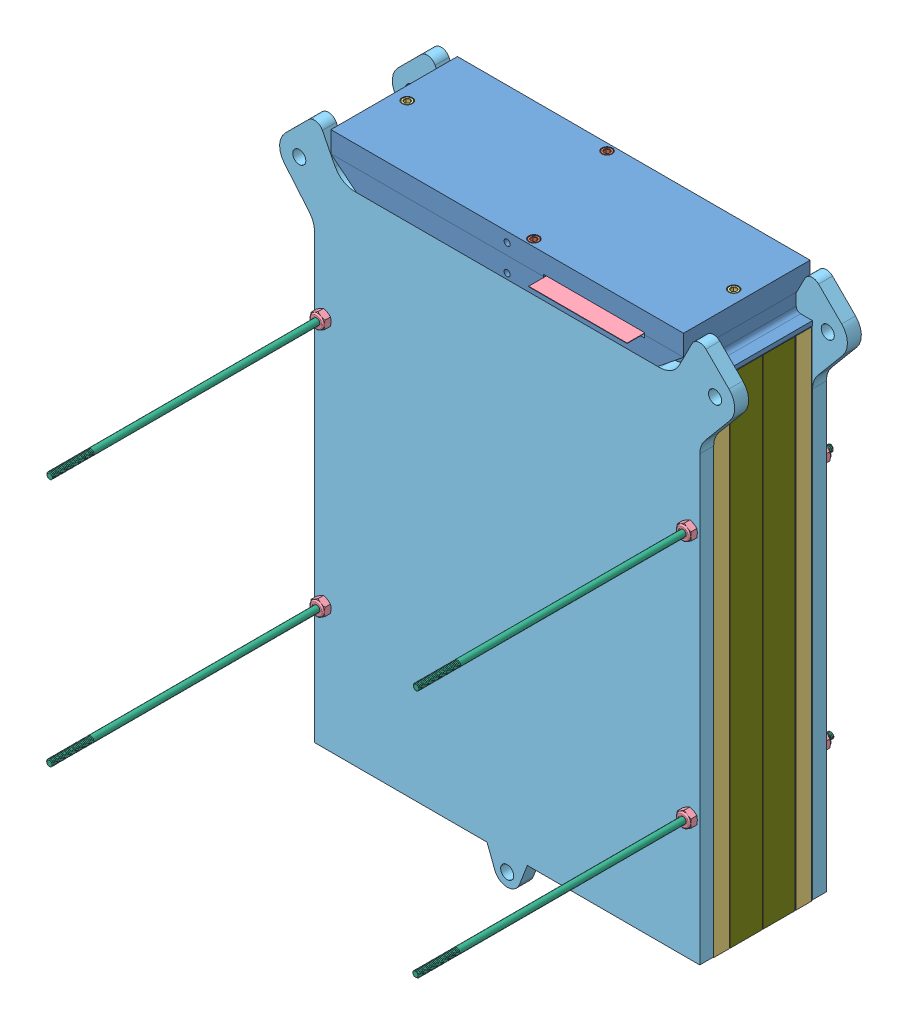
SolidWorks assembly Sixer Stack, configuration Default. Lengths in mm.
Overall size (208.05 259.69 190.91).
93 component instances, 24 part files, 52 mates.
Components (placement in the parent):
- Tab Cover Sixer-1: Tab Cover Sixer [Default] at (178.2277 374.9733 381.1119) x (-1 0 0) z (0 -1 0) size (176.05 57.86 19.05)
- Steel 4-40 1in-1: Steel 4-40 1in [91251A115] at (187.2754 356.1983 406.8676) x (1 0 0) z (0 -1 0) size (4.65 4.65 28.67)
- Steel 4-40 1in-4: Steel 4-40 1in [91251A115] at (169.18 356.1983 355.3562) x (1 0 0) z (0 -1 0) size (4.65 4.65 28.67)
- Socket 4-40 0.625in-1: Socket 4-40 0.625in [91251A112] at (252.8327 365.7233 381.1119) x (-0.701547 0 0.712623) z (0 -1 0) size (4.65 4.65 19.13)
- Socket 4-40 0.625in-2: Socket 4-40 0.625in [91251A112] at (103.6227 365.7233 381.1119) x (1 0 0) z (0 -1 0) size (4.65 4.65 19.13)
- Steel Nylon-Insert Locknut 4-40-15: Steel Nylon-Insert Locknut 4-40 [90631A005] at (103.6227 372.9733 381.1119) x (-1 0 0) z (0 0 1) size (6.35 3.66 7.33)
- Steel Nylon-Insert Locknut 4-40-16: Steel Nylon-Insert Locknut 4-40 [90631A005] at (252.8327 372.9733 381.1119) x (-0.5 0 -0.866025) z (-0.866025 0 0.5) size (6.35 3.66 7.33)
- Two Cell Module-1: Two Cell Module [Default] at (101.24 129.6114 180.5218) size (176.05 244.65 23.04)
  - Cell Tab Config A-1: Cell Tab Config A [Default<As Machined>] at (76.9877 122.2307 189.17) size (160.6 237.16 14.14)
  - Cell Tab Config B-1: Cell Tab Config B [Default<As Machined>] at (76.9877 122.2307 196.6669) x (-1 0 0) z (0 0 -1) size (160.6 237.16 14.15)
  - Tab Load Spreader-1: Tab Load Spreader [Default] at (116.6877 245.8907 190.2131) x (-1 0 0) z (0 1 0) size (56.96 6.41 2.54)
  - Tab Load Spreader-2: Tab Load Spreader [Default] at (37.2877 245.8907 182.7051) x (-1 0 0) z (0 1 0) size (56.96 6.41 2.54)
  - Tab Load Spreader-3: Tab Load Spreader [Default] at (116.6877 242.3507 190.2131) x (-1 0 0) z (0 1 0) size (56.96 6.41 2.54)
  - Tab Load Spreader-4: Tab Load Spreader [Default] at (37.2877 242.3507 182.7051) x (-1 0 0) z (0 1 0) size (56.96 6.41 2.54)
  - Steel Toplock 6-32 Grade 2-1: Steel Toplock 6-32 Grade 2 [91837A008] at (141.9657 242.3507 190.2131) x (1 0 0) z (0 -1 0) size (7.94 9.17 3.14)
  - Steel 6-32 0.4375in-1: Steel 6-32 0.4375in [91251A178] at (141.9657 237.3182 190.2131) x (1 0 0) z (0 -1 0) size (5.74 5.74 15.07)
  - Steel Toplock 6-32 Grade 2-2: Steel Toplock 6-32 Grade 2 [91837A008] at (91.4097 242.3507 190.2131) x (1 0 0) z (0 -1 0) size (7.94 9.17 3.14)
  - Steel Toplock 6-32 Grade 2-3: Steel Toplock 6-32 Grade 2 [91837A008] at (62.5657 242.3507 182.7051) x (1 0 0) z (0 -1 0) size (7.94 9.17 3.14)
  - Steel Toplock 6-32 Grade 2-4: Steel Toplock 6-32 Grade 2 [91837A008] at (12.0097 242.3507 182.7051) x (1 0 0) z (0 -1 0) size (7.94 9.17 3.14)
  - Steel 6-32 0.4375in-2: Steel 6-32 0.4375in [91251A178] at (91.4097 237.3182 190.2131) x (1 0 0) z (0 -1 0) size (5.74 5.74 15.07)
  - Steel 6-32 0.4375in-3: Steel 6-32 0.4375in [91251A178] at (62.5657 237.3182 182.7051) x (1 0 0) z (0 -1 0) size (5.74 5.74 15.07)
  - Steel 6-32 0.4375in-4: Steel 6-32 0.4375in [91251A178] at (12.0097 237.3182 182.7051) x (1 0 0) z (0 -1 0) size (5.74 5.74 15.07)
  - Cell Board Middle-1: Cell Board Middle [Default] at (76.9876 244.3032 188.87) x (-1 0 0) z (0 0 1) size (20.32 17.15 2.64)
  - Cell Board Middle-2: Cell Board Middle [Default] at (76.9876 244.3032 196.3669) size (20.32 17.15 2.64)
  - Repeating Frame Outer-1: Repeating Frame Outer [Default] at (76.9877 115.9807 197.9829) size (175.3 227.13 1.59)
  - Repeating Frame Outer-2: Repeating Frame Outer [Default] at (76.9877 115.9807 186.2665) size (175.3 227.13 1.59)
  - Repeating Frame Inner-1: Repeating Frame Inner [Default] at (76.9877 115.9807 190.0169) size (175.3 227.13 6.35)
  - Insulation Film Back-1: Insulation Film Back [Default] at (76.9877 121.9827 185.62) x (-1 0 0) z (0 0 -1) size (176.05 227.37 0.51)
  - Insulation Film Full-1: Insulation Film Full [Default] at (76.9876 122.0664 200.2855) x (-1 0 0) z (0 0 -1) size (176.05 227.37 14.77)
  - Cell Load Spreader-1: Cell Load Spreader [Default] at (76.9877 115.9807 192.72) size (154 205.5 0.4)
  - Heat Sink Full-1: Heat Sink Full [Default] at (76.9877 122.0321 200.5903) x (-1 0 0) z (0 0 -1) size (176.05 227.3 14.7)
- Positive End Module-1: Positive End Module [Default] at (225.9097 129.8563 535.5842) x (-1 0 0) z (0 0 -1) size (176.05 244.65 21.69)
  - Cell Tab Config B Positive End-1: Cell Tab Config B Positive End [Default<As Machined>] at (47.682 121.9858 173.4343) size (160.6 236.86 21.69)
  - Repeating Frame Outer-1: Repeating Frame Outer [Default] at (47.682 115.7358 170.5308) size (175.3 227.13 1.59)
  - Repeating Frame Outer-2: Repeating Frame Outer [Default] at (47.682 115.7358 175.3218) size (175.3 227.13 1.59)
  - Repeating Frame Outer-3: Repeating Frame Outer [Default] at (47.682 115.7358 173.7343) size (175.3 227.13 1.59)
  - Cell Board End-1: Cell Board End [Default] at (47.682 239.9308 169.3243) x (-1 0 0) z (0 0 1) size (20.32 25.4 3.91)
  - Insulation Film Half-1: Insulation Film Half [Default] at (47.682 121.8215 169.8157) size (176.05 227.37 7.27)
  - Insulation Film End-1: Insulation Film End [Default] at (47.682 115.7358 176.9843) size (154 205.5 0.07)
  - Heat Sink Half-1: Heat Sink Half [Default] at (47.682 121.7872 169.5109) size (176.05 227.3 7.2)
- Negative End Module Even-2: Negative End Module Even [Default] at (88.6187 141.9749 216.0971) size (176.05 244.65 28.29)
  - Cell Tab Config A Negative End-1: Cell Tab Config A Negative End [Default<As Machined>] at (89.6089 109.8672 183.6722) size (160.6 237.16 26.91)
  - Tab Load Spreader-1: Tab Load Spreader [Default] at (49.9089 233.5272 177.2072) x (1 0 0) z (0 1 0) size (56.96 6.41 2.54)
  - Tab Load Spreader-2: Tab Load Spreader [Default] at (49.9089 232.5272 177.2072) x (1 0 0) z (0 -1 0) size (56.96 6.41 2.54)
  - Steel Toplock 6-32 Grade 2-1: Steel Toplock 6-32 Grade 2 [91837A008] at (24.6309 229.9872 177.2072) x (1 0 0) z (0 -1 0) size (7.94 9.17 3.14)
  - Steel Toplock 6-32 Grade 2-2: Steel Toplock 6-32 Grade 2 [91837A008] at (75.1869 229.9872 177.2072) x (1 0 0) z (0 -1 0) size (7.94 9.17 3.14)
  - Steel 6-32 0.4375in-1: Steel 6-32 0.4375in [91251A178] at (24.6309 224.9547 177.2072) x (1 0 0) z (0 -1 0) size (5.74 5.74 15.07)
  - Steel 6-32 0.4375in-2: Steel 6-32 0.4375in [91251A178] at (75.1869 224.9547 177.2072) x (1 0 0) z (0 -1 0) size (5.74 5.74 15.07)
  - Repeating Frame Outer-1: Repeating Frame Outer [Default] at (89.6089 103.6172 185.5597) size (175.3 227.13 1.59)
  - Repeating Frame Outer-2: Repeating Frame Outer [Default] at (89.6089 103.6172 183.9722) size (175.3 227.13 1.59)
  - Repeating Frame Outer-3: Repeating Frame Outer [Default] at (89.6089 103.6172 180.7687) size (175.3 227.13 1.59)
  - Insulation Film Back-1: Insulation Film Back [Default] at (89.609 109.6192 180.1222) x (-1 0 0) z (0 0 -1) size (176.05 227.37 0.51)
  - Insulation Film Half-1: Insulation Film Half [Default] at (89.6089 109.703 187.2908) x (-1 0 0) z (0 0 -1) size (176.05 227.37 7.27)
  - Cell Board End-1: Cell Board End [Default] at (89.6089 227.8122 179.5622) x (-1 0 0) z (0 0 1) size (20.32 25.4 3.91)
  - Heat Sink Half-1: Heat Sink Half [Default] at (89.6089 109.6686 187.5956) x (-1 0 0) z (0 0 -1) size (176.05 227.3 7.2)
- Two Cell Module-2: Two Cell Module [Default] at (101.24 129.6114 195.5604) size (176.05 244.65 23.04)
  - Cell Tab Config A-1: Cell Tab Config A [Default<As Machined>] at (76.9877 122.2307 189.17) size (160.6 237.16 14.14)
  - Cell Tab Config B-1: Cell Tab Config B [Default<As Machined>] at (76.9877 122.2307 196.6669) x (-1 0 0) z (0 0 -1) size (160.6 237.16 14.15)
  - Tab Load Spreader-1: Tab Load Spreader [Default] at (116.6877 245.8907 190.2131) x (-1 0 0) z (0 1 0) size (56.96 6.41 2.54)
  - Tab Load Spreader-2: Tab Load Spreader [Default] at (37.2877 245.8907 182.7051) x (-1 0 0) z (0 1 0) size (56.96 6.41 2.54)
  - Tab Load Spreader-3: Tab Load Spreader [Default] at (116.6877 242.3507 190.2131) x (-1 0 0) z (0 1 0) size (56.96 6.41 2.54)
  - Tab Load Spreader-4: Tab Load Spreader [Default] at (37.2877 242.3507 182.7051) x (-1 0 0) z (0 1 0) size (56.96 6.41 2.54)
  - Steel Toplock 6-32 Grade 2-1: Steel Toplock 6-32 Grade 2 [91837A008] at (141.9657 242.3507 190.2131) x (1 0 0) z (0 -1 0) size (7.94 9.17 3.14)
  - Steel 6-32 0.4375in-1: Steel 6-32 0.4375in [91251A178] at (141.9657 237.3182 190.2131) x (1 0 0) z (0 -1 0) size (5.74 5.74 15.07)
  - Steel Toplock 6-32 Grade 2-2: Steel Toplock 6-32 Grade 2 [91837A008] at (91.4097 242.3507 190.2131) x (1 0 0) z (0 -1 0) size (7.94 9.17 3.14)
  - Steel Toplock 6-32 Grade 2-3: Steel Toplock 6-32 Grade 2 [91837A008] at (62.5657 242.3507 182.7051) x (1 0 0) z (0 -1 0) size (7.94 9.17 3.14)
  - Steel Toplock 6-32 Grade 2-4: Steel Toplock 6-32 Grade 2 [91837A008] at (12.0097 242.3507 182.7051) x (1 0 0) z (0 -1 0) size (7.94 9.17 3.14)
  - Steel 6-32 0.4375in-2: Steel 6-32 0.4375in [91251A178] at (91.4097 237.3182 190.2131) x (1 0 0) z (0 -1 0) size (5.74 5.74 15.07)
  - Steel 6-32 0.4375in-3: Steel 6-32 0.4375in [91251A178] at (62.5657 237.3182 182.7051) x (1 0 0) z (0 -1 0) size (5.74 5.74 15.07)
  - Steel 6-32 0.4375in-4: Steel 6-32 0.4375in [91251A178] at (12.0097 237.3182 182.7051) x (1 0 0) z (0 -1 0) size (5.74 5.74 15.07)
  - Cell Board Middle-1: Cell Board Middle [Default] at (76.9876 244.3032 188.87) x (-1 0 0) z (0 0 1) size (20.32 17.15 2.64)
  - Cell Board Middle-2: Cell Board Middle [Default] at (76.9876 244.3032 196.3669) size (20.32 17.15 2.64)
  - Repeating Frame Outer-1: Repeating Frame Outer [Default] at (76.9877 115.9807 197.9829) size (175.3 227.13 1.59)
  - Repeating Frame Outer-2: Repeating Frame Outer [Default] at (76.9877 115.9807 186.2665) size (175.3 227.13 1.59)
  - Repeating Frame Inner-1: Repeating Frame Inner [Default] at (76.9877 115.9807 190.0169) size (175.3 227.13 6.35)
  - Insulation Film Back-1: Insulation Film Back [Default] at (76.9877 121.9827 185.62) x (-1 0 0) z (0 0 -1) size (176.05 227.37 0.51)
  - Insulation Film Full-1: Insulation Film Full [Default] at (76.9876 122.0664 200.2855) x (-1 0 0) z (0 0 -1) size (176.05 227.37 14.77)
  - Cell Load Spreader-1: Cell Load Spreader [Default] at (76.9877 115.9807 192.72) size (154 205.5 0.4)
  - Heat Sink Full-1: Heat Sink Full [Default] at (76.9877 122.0321 200.5903) x (-1 0 0) z (0 0 -1) size (176.05 227.3 14.7)
- End Plate-1: End Plate [Default] at (178.2277 251.7959 358.5312) size (208.05 259.6 6.35)
- End Plate-2: End Plate [Default] at (178.2276 251.7959 403.6927) x (-1 0 0) z (0 0 -1) size (208.05 259.6 6.35)
- Threaded Rod-1: Threaded Rod [Default] at (94.5077 308.6221 345.8312) x (0.372192 -0.928156 0) z (0 0 1) size (2.99 3.3 190.4)
- Threaded Rod-2: Threaded Rod [Default] at (94.5077 194.9697 345.8312) x (-0.41615 -0.909296 0) z (0 0 1) size (2.99 3.3 190.4)
- Threaded Rod-3: Threaded Rod [Default] at (261.9477 194.9697 345.8312) x (-0.872978 0.487759 0) z (0 0 1) size (2.99 3.3 190.4)
- Threaded Rod-4: Threaded Rod [Default] at (261.9477 308.6221 345.8312) x (0.960246 -0.279155 0) z (0 0 1) size (2.99 3.3 190.4)
- Steel Nylon-Insert Locknut 4-40-3: Steel Nylon-Insert Locknut 4-40 [90631A005] at (94.5076 308.6221 410.0427) x (1 0 0) z (0 -1 0) size (6.35 3.66 7.33)
- Steel Nylon-Insert Locknut 4-40-4: Steel Nylon-Insert Locknut 4-40 [90631A005] at (261.9476 308.6221 410.0427) x (1 0 0) z (0 -1 0) size (6.35 3.66 7.33)
- Steel Nylon-Insert Locknut 4-40-5: Steel Nylon-Insert Locknut 4-40 [90631A005] at (261.9476 194.9697 410.0427) x (1 0 0) z (0 -1 0) size (6.35 3.66 7.33)
- Steel Nylon-Insert Locknut 4-40-6: Steel Nylon-Insert Locknut 4-40 [90631A005] at (94.5076 194.9697 410.0427) x (1 0 0) z (0 -1 0) size (6.35 3.66 7.33)
- Steel Nylon-Insert Locknut 4-40-7: Steel Nylon-Insert Locknut 4-40 [90631A005] at (261.9477 308.6221 352.1812) x (1 0 0) z (0 1 0) size (6.35 3.66 7.33)
- Steel Nylon-Insert Locknut 4-40-8: Steel Nylon-Insert Locknut 4-40 [90631A005] at (94.5077 308.6221 352.1812) x (1 0 0) z (0 1 0) size (6.35 3.66 7.33)
- Steel Nylon-Insert Locknut 4-40-9: Steel Nylon-Insert Locknut 4-40 [90631A005] at (94.5077 194.9697 352.1812) x (1 0 0) z (0 1 0) size (6.35 3.66 7.33)
- Steel Nylon-Insert Locknut 4-40-10: Steel Nylon-Insert Locknut 4-40 [90631A005] at (261.9477 194.9697 352.1812) x (1 0 0) z (0 1 0) size (6.35 3.66 7.33)
Mates (geometry in assembly coordinates):
- Coincident5: coincident anti-aligned: plane of Tab Cover Sixer-1 through (178.2277 365.4483 381.1119) normal (0 -1 0); plane of End Plate-2 through (178.2276 365.4483 410.0427) normal (0 1 0)
- Concentric2: concentric anti-aligned: circle of Threaded Rod-4; circle of End Plate-1
- Concentric3: concentric anti-aligned: circle of Threaded Rod-3; circle of End Plate-1
- Concentric4: concentric aligned: circle of Threaded Rod-2; circle of End Plate-1
- Concentric5: concentric aligned: circle of Threaded Rod-1; circle of End Plate-1
- Distance1: distance = 6.35 mm aligned: plane of Threaded Rod-3 through (261.9477 194.9697 345.8312) normal (0 0 -1); plane of End Plate-1 through (178.2277 251.7959 352.1812) normal (0 0 -1)
- Distance2: distance = 6.35 mm aligned: plane of Threaded Rod-2 through (94.5077 194.9697 345.8312) normal (0 0 -1); plane of End Plate-1 through (178.2277 251.7959 352.1812) normal (0 0 -1)
- Distance3: distance = 6.35 mm aligned: plane of Threaded Rod-1 through (94.5077 308.6221 345.8312) normal (0 0 -1); plane of End Plate-1 through (178.2277 251.7959 352.1812) normal (0 0 -1)
- Distance4: distance = 6.35 mm aligned: plane of Threaded Rod-4 through (261.9477 308.6221 345.8312) normal (0 0 -1); plane of End Plate-1 through (178.2277 251.7959 352.1812) normal (0 0 -1)
- Concentric26: concentric aligned: circle of Steel Nylon-Insert Locknut 4-40-6; circle of End Plate-2
- Coincident59: coincident anti-aligned: plane of End Plate-2 through (178.2276 251.7959 410.0427) normal (0 0 1); plane of Steel Nylon-Insert Locknut 4-40-6 through (94.5076 198.6359 410.0427) normal (0 0 -1)
- Concentric27: concentric aligned: circle of Steel Nylon-Insert Locknut 4-40-3; circle of End Plate-2
- Coincident60: coincident anti-aligned: plane of End Plate-2 through (178.2276 251.7959 410.0427) normal (0 0 1); plane of Steel Nylon-Insert Locknut 4-40-3 through (94.5076 312.2883 410.0427) normal (0 0 -1)
- Concentric28: concentric anti-aligned: circle of Steel Nylon-Insert Locknut 4-40-4; circle of End Plate-2
- Coincident62: coincident anti-aligned: plane of End Plate-2 through (178.2276 251.7959 410.0427) normal (0 0 1); plane of Steel Nylon-Insert Locknut 4-40-4 through (261.9476 312.2883 410.0427) normal (0 0 -1)
- Concentric29: concentric anti-aligned: circle of Steel Nylon-Insert Locknut 4-40-5; circle of End Plate-2
- Coincident63: coincident anti-aligned: plane of End Plate-2 through (178.2276 251.7959 410.0427) normal (0 0 1); plane of Steel Nylon-Insert Locknut 4-40-5 through (261.9476 198.6359 410.0427) normal (0 0 -1)
- Concentric30: concentric aligned: circle of Steel Nylon-Insert Locknut 4-40-7; circle of End Plate-1
- Coincident64: coincident anti-aligned: plane of End Plate-1 through (178.2277 251.7959 352.1812) normal (0 0 -1); plane of Steel Nylon-Insert Locknut 4-40-7 through (261.9477 304.9559 352.1812) normal (0 0 1)
- Concentric31: concentric aligned: circle of Steel Nylon-Insert Locknut 4-40-10; circle of End Plate-1
- Coincident65: coincident anti-aligned: plane of End Plate-1 through (178.2277 251.7959 352.1812) normal (0 0 -1); plane of Steel Nylon-Insert Locknut 4-40-10 through (261.9477 191.3035 352.1812) normal (0 0 1)
- Concentric32: concentric anti-aligned: circle of Steel Nylon-Insert Locknut 4-40-9; circle of End Plate-1
- Coincident66: coincident anti-aligned: plane of End Plate-1 through (178.2277 251.7959 352.1812) normal (0 0 -1); plane of Steel Nylon-Insert Locknut 4-40-9 through (94.5077 191.3035 352.1812) normal (0 0 1)
- Concentric33: concentric anti-aligned: circle of Steel Nylon-Insert Locknut 4-40-8; circle of End Plate-1
- Coincident67: coincident anti-aligned: plane of End Plate-1 through (178.2277 251.7959 352.1812) normal (0 0 -1); plane of Steel Nylon-Insert Locknut 4-40-8 through (94.5077 304.9559 352.1812) normal (0 0 1)
- Concentric39: concentric anti-aligned: circle of Tab Cover Sixer-1; circle of Steel 4-40 1in-1
- Coincident70: coincident anti-aligned: plane of Tab Cover Sixer-1 through (187.2754 381.5983 406.8676) normal (0 1 0); plane of Steel 4-40 1in-1 through (187.2754 381.5983 406.8676) normal (0 -1 0)
- Concentric42: concentric anti-aligned: circle of Tab Cover Sixer-1; circle of Steel 4-40 1in-4
- Coincident73: coincident anti-aligned: plane of Tab Cover Sixer-1 through (169.18 381.5983 355.3562) normal (0 1 0); plane of Steel 4-40 1in-4 through (169.18 381.5983 355.3562) normal (0 -1 0)
- Concentric45: concentric anti-aligned: circle of Tab Cover Sixer-1; circle of Socket 4-40 0.625in-1
- Coincident75: coincident anti-aligned: plane of Tab Cover Sixer-1 through (252.8327 381.5983 381.1119) normal (0 1 0); plane of Socket 4-40 0.625in-1 through (252.8327 381.5983 381.1119) normal (0 -1 0)
- Concentric46: concentric anti-aligned: circle of Tab Cover Sixer-1; circle of Socket 4-40 0.625in-2
- Coincident76: coincident anti-aligned: plane of Tab Cover Sixer-1 through (103.6227 381.5983 381.1119) normal (0 1 0); plane of Socket 4-40 0.625in-2 through (103.6227 381.5983 381.1119) normal (0 -1 0)
- Coincident77: coincident anti-aligned: plane of Steel Nylon-Insert Locknut 4-40-15 through (103.6227 372.9733 377.4458) normal (0 1 0); plane of Tab Cover Sixer-1 through (178.2277 372.9733 381.1119) normal (0 -1 0)
- Parallel3: parallel anti-aligned: plane of Tab Cover Sixer-1 through (99.6227 369.2733 381.1119) normal (1 0 0); plane of Steel Nylon-Insert Locknut 4-40-15 through (100.4477 369.4014 382.945) normal (-1 0 0)
- Concentric48: concentric aligned: circle of Tab Cover Sixer-1; circle of Steel Nylon-Insert Locknut 4-40-15
- Concentric49: concentric aligned: circle of Steel Nylon-Insert Locknut 4-40-16; circle of Tab Cover Sixer-1
- Parallel4: parallel anti-aligned: plane of Tab Cover Sixer-1 through (249.6327 369.2733 381.1119) normal (1 0 0); plane of Steel Nylon-Insert Locknut 4-40-16 through (249.6577 369.4014 382.945) normal (-1 0 0)
- Coincident79: coincident anti-aligned: plane of Tab Cover Sixer-1 through (178.2277 372.9733 381.1119) normal (0 -1 0); plane of Steel Nylon-Insert Locknut 4-40-16 through (256.0077 372.9733 379.2789) normal (0 1 0)
- Coincident99: coincident anti-aligned: plane of End Plate-2 through (178.2276 365.4483 410.0427) normal (0 1 0); plane of Tab Cover Sixer-1 through (178.2277 365.4483 381.1119) normal (0 -1 0)
- Coincident103: coincident anti-aligned: plane of Tab Cover Sixer-1; plane of End Plate-1 through (178.2277 251.7959 358.5312) normal (1 0 0)
- Concentric52: concentric aligned: circle of Two Cell Module-1/Insulation Film Back-1; circle of Positive End Module-1/Heat Sink Half-1
- Coincident109: coincident aligned: circle of Two Cell Module-1/Insulation Film Back-1; circle of Positive End Module-1/Heat Sink Half-1
- Concentric53: concentric aligned: circle of Positive End Module-1/Repeating Frame Outer-2; circle of End Plate-1
- Concentric56: concentric aligned: circle of Positive End Module-1/Repeating Frame Outer-2; circle of End Plate-1
- Coincident116: coincident anti-aligned: plane of Positive End Module-1/Insulation Film End-1 through (178.2277 245.5921 358.5312) normal (0 0 -1); plane of End Plate-1 through (178.2277 251.7959 358.5312) normal (0 0 1)
- Coincident117: coincident aligned: plane of Tab Cover Sixer-1 through (258.8327 365.4483 352.1812) normal (0 0 -1); plane of End Plate-1 through (178.2277 251.7959 352.1812) normal (0 0 -1)
- Concentric59: concentric aligned: circle of End Plate-2; circle of Negative End Module Even-2/Heat Sink Half-1
- Coincident129: coincident aligned: circle of End Plate-2; circle of Negative End Module Even-2/Heat Sink Half-1
- Coincident132: coincident anti-aligned: plane of Tab Cover Sixer-1 through (178.2277 365.4483 381.1119) normal (0 -1 0); plane of End Plate-1 through (178.2277 365.4483 352.1812) normal (0 1 0)
- Coincident139: coincident anti-aligned: plane of Negative End Module Even-2/Insulation Film Back-1 through (178.2277 251.5941 396.1507) normal (0 0 -1); plane of Two Cell Module-2/Heat Sink Full-1 through (178.2276 251.6435 396.1507) normal (0 0 1)
- Coincident140: coincident aligned: plane of Negative End Module Even-2/Heat Sink Half-1 through (90.2028 365.1435 396.4879) normal (-1 0 0); plane of Two Cell Module-2/Heat Sink Full-1 through (90.2028 365.1435 381.449) normal (-1 0 0)
